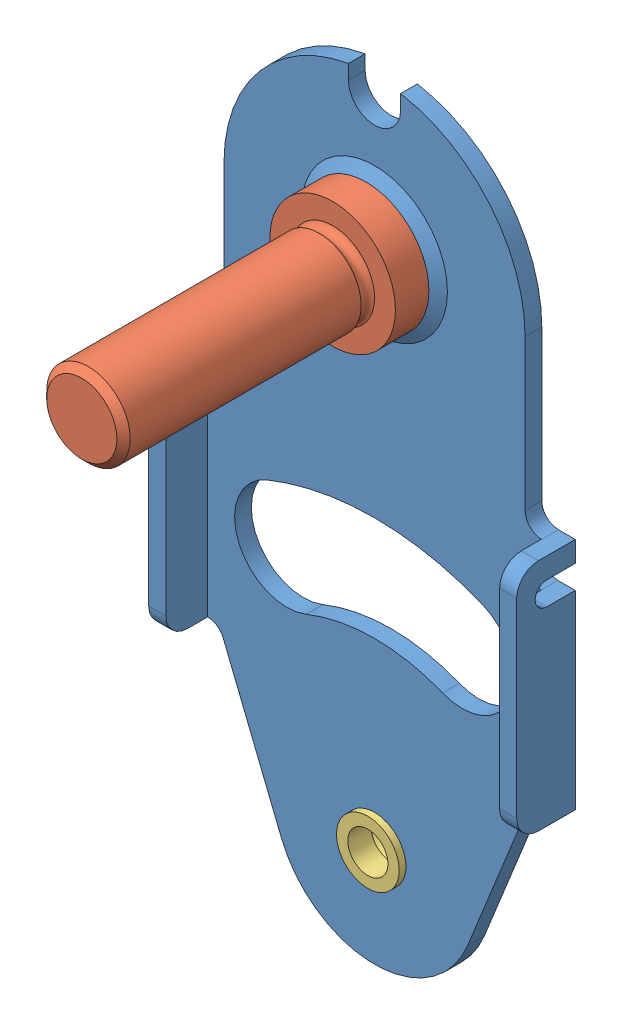
SolidWorks assembly 74-003, configuration Default. Lengths in mm.
Overall size (27.94 58.25 28.58).
3 component instances, 3 part files, 4 mates.
Components (placement in the parent):
- 41-001rA-1: 41-001rA [Default] at (1.173 -21.8549 14.2289) size (27.94 58.25 4.45)
- 31-004rA-1: 31-004rA [Default] at (1.173 17.5151 14.3559) x (-0.860593 0.509293 0) z (0.509293 0.860593 0) size (9.53 23.37 9.53)
- 31-001rA-1: 31-001rA [Default] at (1.173 -21.8549 16.0069) x (1 0 0) z (0 1 0) size (6.3 6.86 6.3)
Mates (geometry in assembly coordinates):
- Concentric1: concentric aligned: cylinder of 41-001rA-1 through (1.173 17.5151 15.4989) axis (0 0 -1) radius 2.3876; cylinder of 31-004rA-1 through (1.173 17.5151 14.3559) axis (0 0 -1) radius 2.3749
- Coincident1: coincident anti-aligned: plane of 41-001rA-1 through (1.173 17.5151 16.1339) normal (0 0 1); plane of 31-004rA-1 through (-2.9256 19.9406 16.1339) normal (0 0 -1)
- Concentric2: concentric anti-aligned: cylinder of 41-001rA-1 through (1.173 -21.8549 15.4989) axis (0 0 -1) radius 2.3876; cylinder of 31-001rA-1 through (1.173 -21.8549 16.0069) axis (0 0 1) radius 2.3749
- Coincident2: coincident anti-aligned: plane of 41-001rA-1 through (13.8398 -14.2349 14.2289) normal (0 0 -1); plane of 31-001rA-1 through (4.3226 -21.8549 14.2289) normal (0 0 1)
